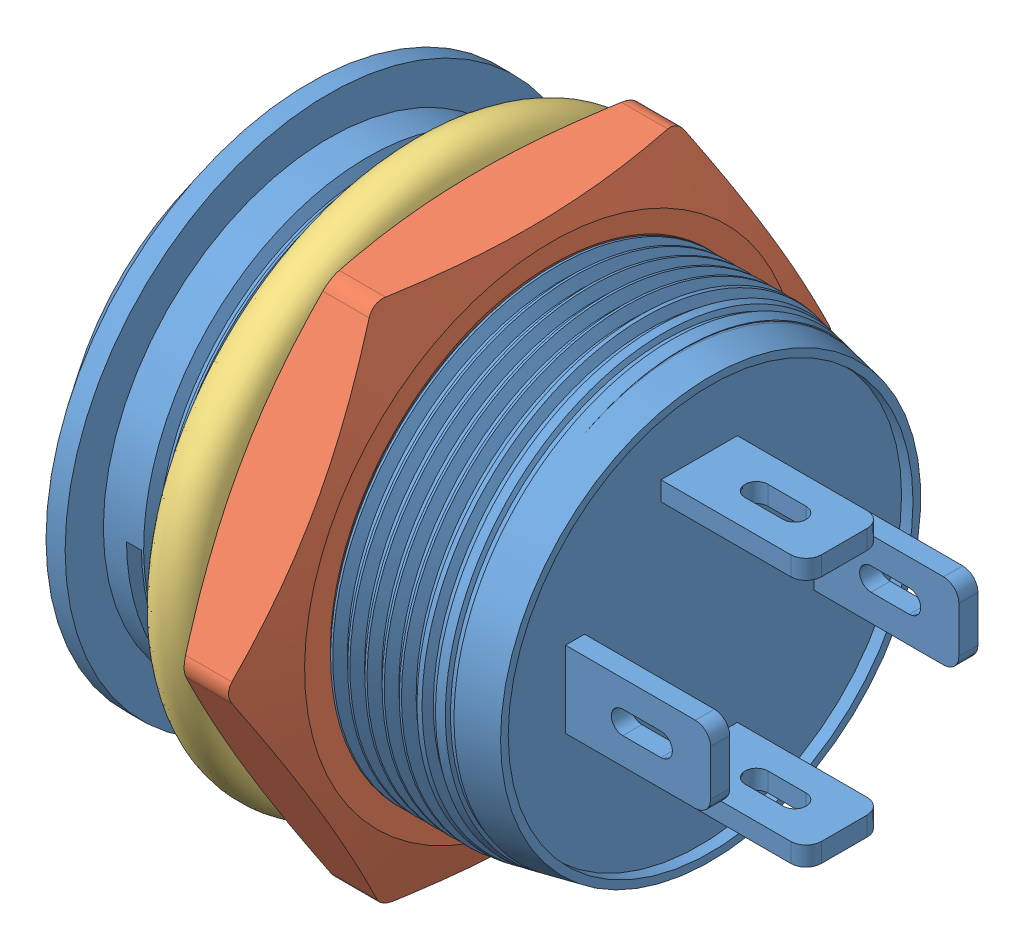
SolidWorks assembly Push_btn_asm, configuration По умолчанию. Lengths in mm.
Overall size (15.2 20.63 19.95).
3 component instances, 3 part files, 3 mates.
Components (placement in the parent):
- Push_btn-1: Push_btn [По умолчанию] at origin size (15.2 13.8 13.8)
- Push_btn_nut-1: Push_btn_nut [По умолчанию] at (6.3869 0 0) x (0 -0.513678 0.857983) z (0 0.857983 0.513678) size (13.8 2.61 15.78)
- Sealing_ring-1: Sealing_ring [По умолчанию] at (4.5369 0 0) x (0 0.94412 -0.329601) z (0 -0.329601 -0.94412) size (14.6 1.4 14.6)
Mates (geometry in assembly coordinates):
- Совпадение1: coincident anti-aligned: line of Push_btn-1 through (0 16.72 -0.76) axis (0 0 1); line of Гайка_кнопки-1 through (13.8487 0 0) axis (-1 0 0)
- Совпадение2: coincident anti-aligned: line of Push_btn-1 through (0 16.72 -0.76) axis (0 0 1); line of Уплотнительное кольцо-1 through (0 1.65 5.3619) axis (0 0 -1)
- Касательность1: tangent anti-aligned: plane of Гайка_кнопки-1 through (5.2369 0 0) normal (-1 0 0); torus of Уплотнительное кольцо-1
